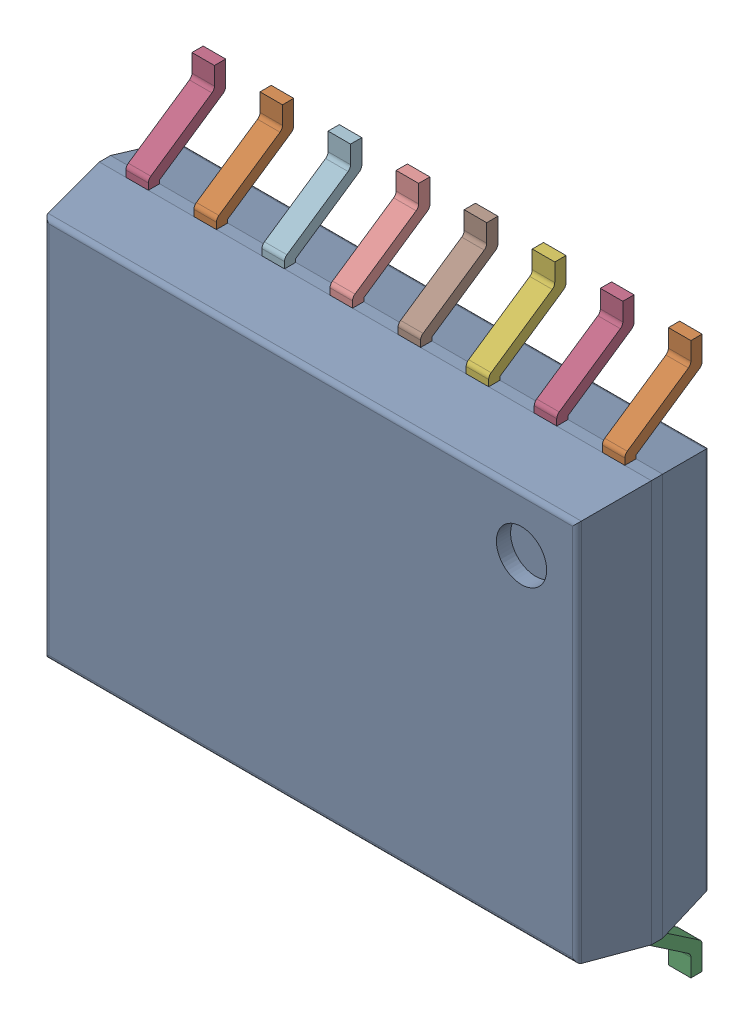
SolidWorks assembly IC4_4.step, configuration Default. Lengths in mm.
Overall size (10.3 10.3 2.65).
3 component instances, 2 part files, 0 mates.
Components (placement in the parent):
- 6383678080.step-1: 6383678080.step [Default] at (91.206 101.397 0) x (0 -1 0) z (0 0 1) size (10.3 10.3 2.65)
  - Body-0_3.step-14: Body-0_3.step [Default] at origin size (7.5 10.3 2.48)
  - PinsArrayLR_4.step-14: PinsArrayLR_4.step [Default] at origin size (10.3 9.31 1.44)
